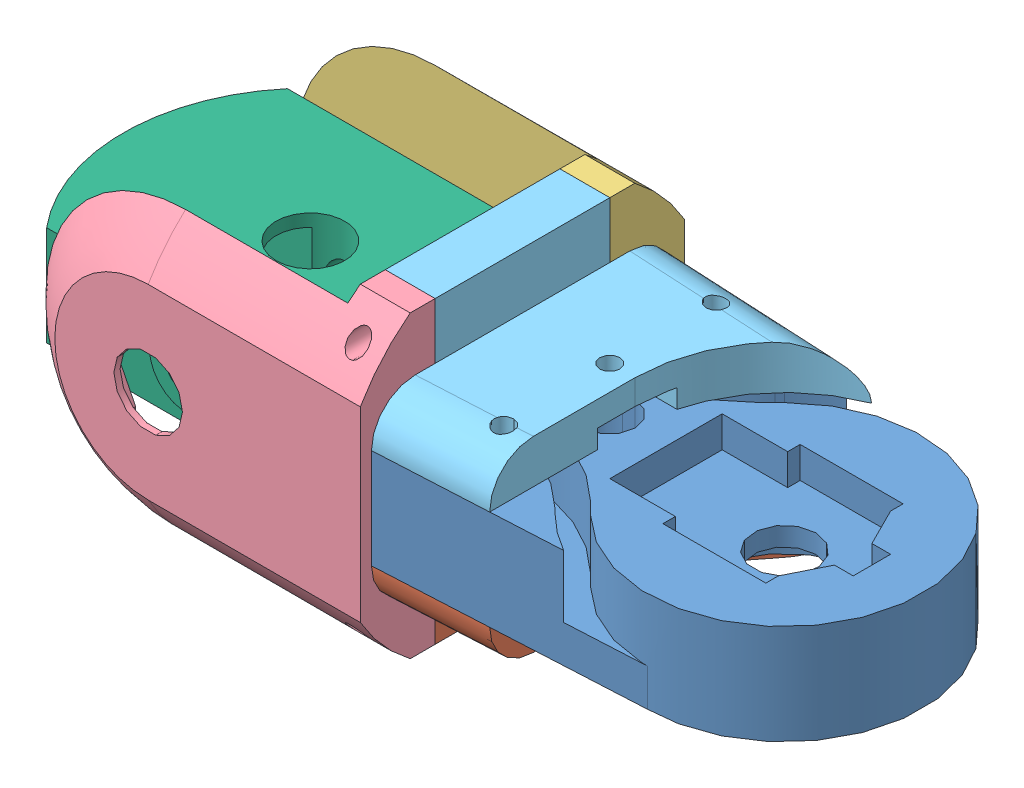
SolidWorks assembly thumbP-assembly, configuration Default. Lengths in mm.
Overall size (64 24 26).
6 component instances, 6 part files, 14 mates.
Components (placement in the parent):
- thumbP-middle-1: thumbP-middle [Default] at (-35.7341 29.3306 13.9435) size (36 8 24.21)
- thumbP-bottom-1: thumbP-bottom [Default] at (-35.7341 29.3306 13.9435) size (21.17 8.41 24.21)
- thumbP-left-1: thumbP-left [Default] at (-35.7341 33.3306 0.9435) size (28.18 24 6)
- thumbP-right-1: thumbP-right [Default] at (-35.7341 33.3306 26.9435) size (28.18 24 6)
- thumbP-top-1: thumbP-top [Default] at (-35.7341 37.3306 13.9435) size (21.17 8.42 24.21)
- thumbP-joint-1: thumbP-joint [Default] at (-54.1244 33.3306 4.2935) size (26 8 22.55)
Mates (geometry in assembly coordinates):
- Concentric1: concentric aligned: cylinder of thumbP-middle-1 through (-11.7341 37.3306 22.4435) axis (0 -1 0) radius 0.8; cylinder of thumbP-top-1 through (-11.7341 40.8306 22.4435) axis (0 -1 0) radius 0.8
- Concentric2: concentric aligned: cylinder of thumbP-middle-1 through (-11.7341 37.3306 5.4435) axis (0 -1 0) radius 0.8; cylinder of thumbP-top-1 through (-11.7341 40.8306 5.4435) axis (0 -1 0) radius 0.8
- Coincident2: coincident anti-aligned: plane of thumbP-middle-1 through (-35.7341 37.3306 13.9435) normal (0 1 0); plane of thumbP-top-1 through (-35.7341 37.3306 13.9435) normal (0 -1 0)
- Concentric3: concentric anti-aligned: cylinder of thumbP-middle-1 through (-11.7341 37.3306 5.4435) axis (0 -1 0) radius 0.8; cylinder of thumbP-bottom-1 through (-11.7341 25.8306 5.4435) axis (0 1 0) radius 0.8
- Concentric4: concentric anti-aligned: cylinder of thumbP-middle-1 through (-11.7341 37.3306 22.4435) axis (0 -1 0) radius 0.8; cylinder of thumbP-bottom-1 through (-11.7341 25.8306 22.4435) axis (0 1 0) radius 0.8
- Coincident3: coincident anti-aligned: plane of thumbP-middle-1 through (-35.7341 29.3306 13.9435) normal (0 -1 0); plane of thumbP-bottom-1 through (-35.7341 29.3306 13.9435) normal (0 1 0)
- Concentric5: concentric anti-aligned: cylinder of thumbP-left-1 through (-20.7341 43.3306 6.9435) axis (0 0 -1) radius 0.8; cylinder of thumbP-top-1 through (-20.7341 43.3306 1.8383) axis (0 0 1) radius 0.8
- Concentric6: concentric anti-aligned: cylinder of thumbP-bottom-1 through (-20.7341 23.3306 1.8383) axis (0 0 1) radius 0.8; cylinder of thumbP-left-1 through (-20.7341 23.3306 6.9435) axis (0 0 -1) radius 0.8
- Coincident4: coincident anti-aligned: plane of thumbP-left-1 through (-35.7341 33.3306 6.9435) normal (0 0 1); plane of thumbP-top-1 through (-35.7341 40.8306 6.9435) normal (0 0 -1)
- Concentric7: concentric aligned: cylinder of thumbP-right-1 through (-20.7341 43.3306 20.9435) axis (0 0 1) radius 0.8; cylinder of thumbP-top-1 through (-20.7341 43.3306 1.8383) axis (0 0 1) radius 0.8
- Concentric8: concentric aligned: cylinder of thumbP-bottom-1 through (-20.7341 23.3306 1.8383) axis (0 0 1) radius 0.8; cylinder of thumbP-right-1 through (-20.7341 23.3306 20.9435) axis (0 0 1) radius 0.8
- Coincident5: coincident anti-aligned: plane of thumbP-right-1 through (-35.7341 33.3306 20.9435) normal (0 0 -1); plane of thumbP-top-1 through (-35.7341 40.8306 20.9435) normal (0 0 1)
- Concentric9: concentric anti-aligned: cylinder of thumbP-left-1 through (-35.7341 33.3306 6.9435) axis (0 0 -1) radius 2.75; cylinder of thumbP-joint-1 through (-35.7341 33.3306 1.2935) axis (0 0 1) radius 2.25
- Distance1: distance = 0.35 mm anti-aligned: plane of thumbP-joint-1 through (-54.1244 33.3306 4.2935) normal (0 0 -1); plane of thumbP-left-1 through (-35.7341 33.3306 3.9435) normal (0 0 1)
